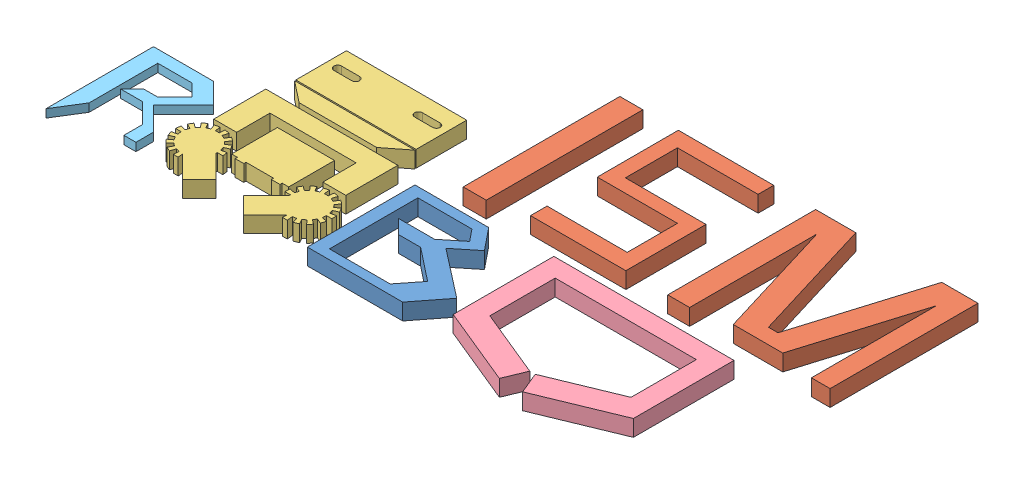
SolidWorks assembly logo, configuration Default. Lengths in mm.
Overall size (392.69 10 186.03).
5 component instances, 5 part files, 4 mates.
Components (placement in the parent):
- B-1: B [Default] at (30.2591 37.6759 54.3672) size (72.72 10 65.76)
- ism-1: ism [Default] at (80.2015 37.6759 -44.7608) size (218.84 10 95.73)
- O-1: O [Default] at (-56.5331 37.6759 43.8261) size (95.48 10 118.37)
- o2-1: o2 [Default] at (133.9604 37.6759 41.7434) size (110.12 10 81.24)
- R-1: R [Default] at (180.4101 37.6759 206.4096) size (49.4 5 65.69)
Mates (geometry in assembly coordinates):
- Distance4: distance = 0 mm aligned: plane of O-1 through (-56.5331 37.6759 43.8261) normal (0 -1 0); plane of B-1 through (30.2591 37.6759 54.3672) normal (0 -1 0)
- Distance5: distance = 0 mm aligned: plane of o2-1 through (133.9604 37.6759 41.7434) normal (0 -1 0); plane of O-1 through (-56.5331 37.6759 43.8261) normal (0 -1 0)
- Distance6: distance = 0 mm aligned: plane of ism-1 through (80.2015 37.6759 -44.7608) normal (0 -1 0); plane of O-1 through (-56.5331 37.6759 43.8261) normal (0 -1 0)
- Distance7: distance = 0 mm aligned: plane of O-1 through (-56.5331 37.6759 43.8261) normal (0 -1 0); plane of R-1 through (180.4101 37.6759 206.4096) normal (0 -1 0)
